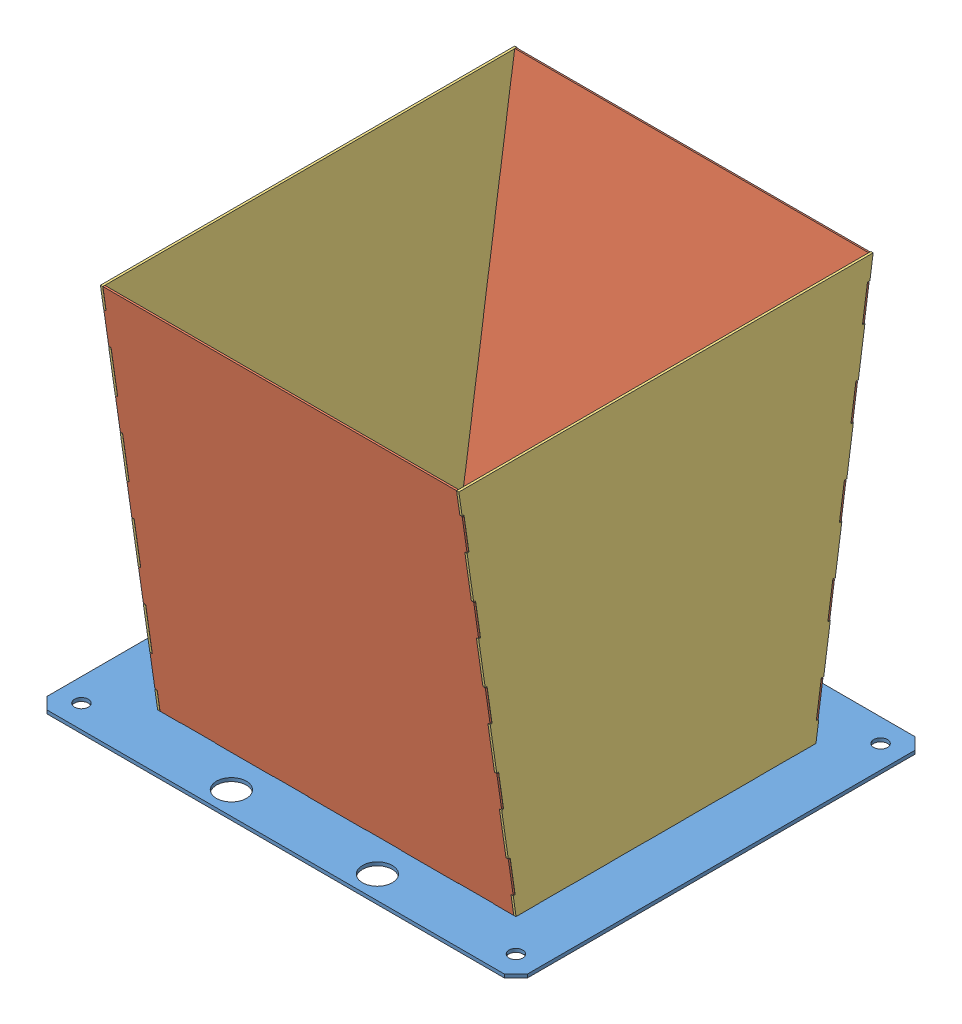
SolidWorks assembly SHRPRO-V1 1200.00-A Basic Hopper assembly, configuration Predeterminado. Lengths in mm.
Overall size (416.5 346.64 359.1).
5 component instances, 3 part files, 13 mates.
Components (placement in the parent):
- SHRPRO-V1 1200.01-A Botton plate hopper-2: SHRPRO-V1 1200.01-A Botton plate hopper [Predeterminado] at origin size (416.5 3 356)
- SHRPRO-V1 1200.02-A Front plate hopper-1: SHRPRO-V1 1200.02-A Front plate hopper [Predeterminado] at (0 170.2051 154.433) x (1 0 0) z (0 -0.989743 -0.142857) size (310.5 1.5 350)
- SHRPRO-V1 1200.03-A Right plate hopper-1: SHRPRO-V1 1200.03-A Right plate hopper [Predeterminado] at (155.25 170.2051 -0.067) x (0 0 -1) z (0 -1 0) size (359 2 346.41)
- SHRPRO-V1 1200.02-A Front plate hopper-2: SHRPRO-V1 1200.02-A Front plate hopper [Predeterminado] at (0 170.4061 -152.4742) x (1 0 0) z (0 -0.989743 0.142857) size (310.5 1.5 350)
- SHRPRO-V1 1200.03-A Right plate hopper-2: SHRPRO-V1 1200.03-A Right plate hopper [Predeterminado] at (-153.25 170.2051 0.034) x (0 0 -1) z (0 -1 0) size (359 2 346.41)
Mates (geometry in assembly coordinates):
- Coordinate2: coordinate: point of SHRPRO-V1 1200.01-A Botton plate hopper-2; point of assembly
- Coincident51: coincident: plane of SHRPRO-V1 1200.01-A Botton plate hopper-2 through (155.25 -3 130) normal (-1 0 0); plane of SHRPRO-V1 1200.03-A Right plate hopper-1 through (155.25 170.2051 -0.067) normal (1 0 0)
- Coincident52: coincident: plane of SHRPRO-V1 1200.01-A Botton plate hopper-2 through (0 -3 0) normal (0 -1 0); plane of SHRPRO-V1 1200.03-A Right plate hopper-1 through (153.25 -3 129.433) normal (0 -1 0)
- Coincident66: coincident: plane of SHRPRO-V1 1200.02-A Front plate hopper-1 through (0 170.2051 154.433) normal (0 -0.142857 0.989743); plane of SHRPRO-V1 1200.03-A Right plate hopper-1 through (153.25 343.4102 179.433) normal (0 -0.142857 0.989743)
- Coincident67: coincident: line of SHRPRO-V1 1200.01-A Botton plate hopper-2 through (155.25 0 -130) axis (-1 0 0); plane of SHRPRO-V1 1200.03-A Right plate hopper-1 through (153.25 -3 -129.567) normal (0 -0.142857 -0.989743)
- Coincident68: coincident: plane of SHRPRO-V1 1200.02-A Front plate hopper-1 through (153.25 -2.7857 127.9484) normal (1 0 0); plane of SHRPRO-V1 1200.03-A Right plate hopper-1 through (153.25 170.2051 -0.067) normal (-1 0 0)
- Coincident75: coincident: plane of SHRPRO-V1 1200.01-A Botton plate hopper-2 through (0 -3 0) normal (0 -1 0); line of SHRPRO-V1 1200.02-A Front plate hopper-1 through (-153.25 -3 129.433) axis (1 0 0)
- Coincident76: coincident: plane of SHRPRO-V1 1200.03-A Right plate hopper-1 through (157.25 16.9959 -130.3314) normal (0 -0.142857 -0.989743); plane of SHRPRO-V1 1200.02-A Front plate hopper-2 through (0 170.4061 -152.4742) normal (0 0.142857 0.989743)
- Coincident78: coincident: plane of SHRPRO-V1 1200.03-A Right plate hopper-1 through (153.25 170.2051 -0.067) normal (-1 0 0); plane of SHRPRO-V1 1200.02-A Front plate hopper-2 through (153.25 -3.0133 -128.9589) normal (1 0 0)
- Coincident79: coincident: plane of SHRPRO-V1 1200.03-A Right plate hopper-1 through (157.25 293.8097 -172.5088) normal (0 0.989743 -0.142857); plane of SHRPRO-V1 1200.02-A Front plate hopper-2 through (157.25 293.9097 -171.816) normal (0 -0.989743 0.142857)
- Coincident81: coincident: plane of SHRPRO-V1 1200.02-A Front plate hopper-1 through (-153.25 -2.7857 127.9484) normal (-1 0 0); plane of SHRPRO-V1 1200.03-A Right plate hopper-2 through (-153.25 170.2051 0.034) normal (1 0 0)
- Coincident82: coincident: plane of SHRPRO-V1 1200.02-A Front plate hopper-1 through (0 170.4194 152.9484) normal (0 0.142857 -0.989743); plane of SHRPRO-V1 1200.03-A Right plate hopper-2 through (-151.25 323.9428 175.1076) normal (0 -0.142857 0.989743)
- Coincident83: coincident: plane of SHRPRO-V1 1200.01-A Botton plate hopper-2 through (0 -3 0) normal (0 -1 0); line of SHRPRO-V1 1200.03-A Right plate hopper-2 through (-155.25 -3 -46.6656) axis (0 0 -1)
